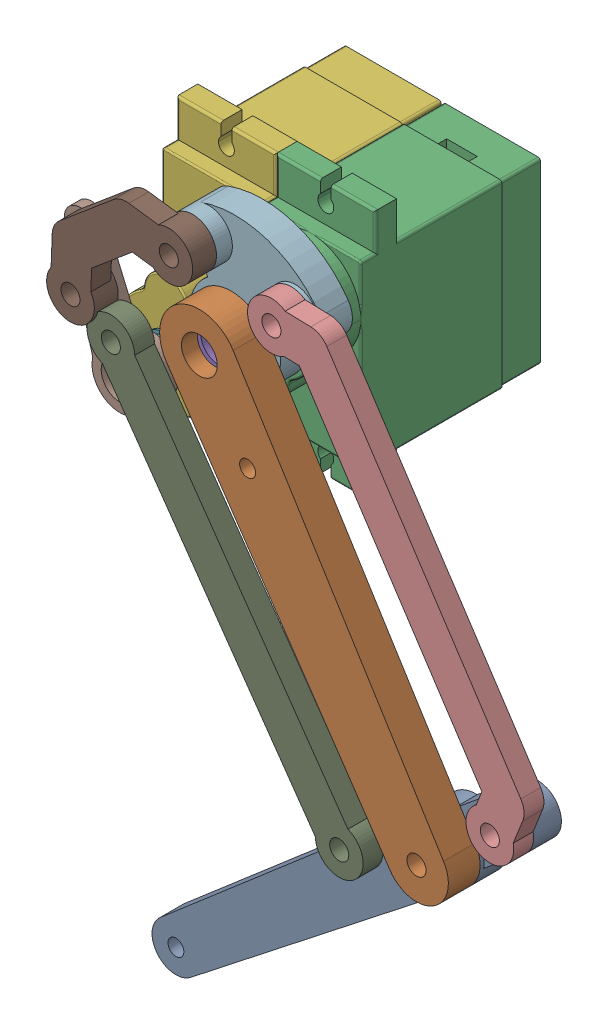
SolidWorks assembly leg_pet bot, configuration Default. Lengths in mm.
Overall size (64.31 93.29 37.3).
16 component instances, 10 part files, 23 mates.
Components (placement in the parent):
- lower_part_leg-1: lower_part_leg [Default] at (33.4104 -25.3824 14.05) x (-0.772475 -0.635046 0) z (0 0 -1) size (61 8 3.5)
- upper_part_leg-1: upper_part_leg [Default] at (6.1 16.5 14.55) x (0.546209 -0.837649 0) z (0 0 1) size (59 10 4)
- MG90servo_assembly(2)^pet bot iteration one-1: MG90servo_assembly(2)^pet bot iteration one [Default] at (12.35 0 -18.25) x (0 1 0) z (1 0 0) size (32.05 32.8 12.51)
  - MG90servo_body(2)^MG90servo_assembly(2)_pet bot iteration one-1: MG90servo_body(2)^MG90servo_assembly(2)_pet bot iteration one [Default] at origin size (32.05 28.5 12.51)
  - MG90servo_shaft(2)^MG90servo_assembly(2)_pet bot iteration one-1: MG90servo_shaft(2)^MG90servo_assembly(2)_pet bot iteration one [Default] at (16.5 28.5 -6.25) x (0.786985 0 0.616972) z (-0.616972 0 0.786985) size (5 4.3 5)
  - MG90servo_gear(2)^MG90servo_assembly(2)_pet bot iteration one-1: MG90servo_gear(2)^MG90servo_assembly(2)_pet bot iteration one [Default] at (16.5 34.45 -6.25) x (0.999514 0 0.031181) z (0.031181 0 -0.999514) (suppressed, hidden)
- microservoArm-1: microservoArm [A3] at (6.1 16.5 16.05) x (0.569885 -0.821724 0) z (0.821724 0.569885 0) size (20.7 3.9 7)
- MG90servo_assembly(2)^pet bot iteration one-2: MG90servo_assembly(2)^pet bot iteration one [Default] at (-12.65 22.75 -18.25) x (0 -1 0) z (-1 0 0) size (32.05 32.8 12.51)
  - MG90servo_body(2)^MG90servo_assembly(2)_pet bot iteration one-1: MG90servo_body(2)^MG90servo_assembly(2)_pet bot iteration one [Default] at origin size (32.05 28.5 12.51)
  - MG90servo_shaft(2)^MG90servo_assembly(2)_pet bot iteration one-1: MG90servo_shaft(2)^MG90servo_assembly(2)_pet bot iteration one [Default] at (16.5 28.5 -6.25) x (0.786985 0 0.616972) z (-0.616972 0 0.786985) size (5 4.3 5)
  - MG90servo_gear(2)^MG90servo_assembly(2)_pet bot iteration one-1: MG90servo_gear(2)^MG90servo_assembly(2)_pet bot iteration one [Default] at (16.5 34.45 -6.25) x (0.999514 0 0.031181) z (0.031181 0 -0.999514) (suppressed, hidden)
- microservoArm-2: microservoArm [A3] at (-6.4 6.25 16.05) x (-0.328049 0.944661 0) z (-0.944661 -0.328049 0) size (20.7 3.9 7)
- connecting_part_leg_2-1: connecting_part_leg_2 [Default] at (-5.0321 12.3438 16.05) x (0.574452 -0.818539 0) z (0 0 1) size (56 6 2.5) (hidden)
- modified connecting rod 3-1: modified connecting rod 3 [Default] at (27.3958 1.8541 15.8) x (0.549575 -0.835444 0) z (0 0 1) size (56 9.5 2.5)
- modified connecting rod-1: modified connecting rod [Default] at (-3.4306 20.7156 17.8) x (-0.764905 -0.644143 0) z (0 0 -1) size (22.17 9.5 3)
- coupler_1-1: coupler_1 [Default] at (6.1 16.5 14.05) x (-0.798551 -0.601927 0) z (0 0 -1) size (18.7 18.24 5.5)
Mates (geometry in assembly coordinates):
- Concentric1: concentric anti-aligned: cylinder of upper_part_leg-1 through (6.1 16.5 8.55) axis (0 0 1) radius 2.25; cylinder of MG90servo_assembly(2)^pet bot iteration one-1/MG90servo_body(2)^MG90servo_assembly(2)_pet bot iteration one-1 through (6.1 16.5 10.25) axis (0 0 -1) radius 6.25
- Coincident3: coincident anti-aligned: plane of upper_part_leg-1 through (6.1 16.5 16.05) normal (0 0 -1); plane of microservoArm-1 through (-2.5623 28.9902 16.05) normal (0 0 1)
- Concentric3: concentric anti-aligned: cylinder of MG90servo_assembly(2)^pet bot iteration one-1/MG90servo_shaft(2)^MG90servo_assembly(2)_pet bot iteration one-1 through (6.1 16.5 11.65) axis (0 0 -1) radius 2.075; cylinder of microservoArm-1 through (6.1 16.5 12.15) axis (0 0 1) radius 2.45
- Coincident4: coincident anti-aligned: plane of MG90servo_assembly(2)^pet bot iteration one-1/MG90servo_shaft(2)^MG90servo_assembly(2)_pet bot iteration one-1 through (6.1 16.5 14.55) normal (0 0 1); plane of microservoArm-1 through (6.1 16.5 14.55) normal (0 0 -1)
- Coincident5: coincident anti-aligned: plane of MG90servo_assembly(2)^pet bot iteration one-1/MG90servo_body(2)^MG90servo_assembly(2)_pet bot iteration one-1 through (-0.15 0 4.5) normal (-1 0 0); plane of MG90servo_assembly(2)^pet bot iteration one-2/MG90servo_body(2)^MG90servo_assembly(2)_pet bot iteration one-1 through (-0.15 22.75 4.5) normal (1 0 0)
- Coincident6: coincident aligned: plane of MG90servo_assembly(2)^pet bot iteration one-1/MG90servo_body(2)^MG90servo_assembly(2)_pet bot iteration one-1 through (12.35 0 4.5) normal (0 0 1); plane of MG90servo_assembly(2)^pet bot iteration one-2/MG90servo_body(2)^MG90servo_assembly(2)_pet bot iteration one-1 through (-12.65 22.75 4.5) normal (0 0 1)
- Concentric4: concentric anti-aligned: cylinder of MG90servo_assembly(2)^pet bot iteration one-2/MG90servo_body(2)^MG90servo_assembly(2)_pet bot iteration one-1 through (-6.4 6.25 10.25) axis (0 0 -1) radius 6.25; cylinder of microservoArm-2 through (-6.4 6.25 12.15) axis (0 0 1) radius 2.45
- Coincident7: coincident anti-aligned: plane of MG90servo_assembly(2)^pet bot iteration one-2/MG90servo_shaft(2)^MG90servo_assembly(2)_pet bot iteration one-1 through (-6.4 6.25 14.55) normal (0 0 1); plane of microservoArm-2 through (-6.4 6.25 14.55) normal (0 0 -1)
- Coincident8: coincident aligned: plane of MG90servo_assembly(2)^pet bot iteration one-1/MG90servo_body(2)^MG90servo_assembly(2)_pet bot iteration one-1 through (12.35 27.4 2.65) normal (0 1 0); plane of MG90servo_assembly(2)^pet bot iteration one-2/MG90servo_body(2)^MG90servo_assembly(2)_pet bot iteration one-1 through (-12.65 27.4 2.65) normal (0 1 0)
- Coincident13: coincident: plane of upper_part_leg-1 through (9.509 18.2893 -8.853) normal (-0.885442 -0.464749 0); line of microservoArm-1 through (16.4057 5.1496 14.65) axis (0 0 1)
- Concentric10: concentric aligned: cylinder of microservoArm-2 through (-9.6149 15.5077 14.65) axis (0 0 1) radius 0.5; cylinder of modified connecting rod-1 through (-9.6149 15.5077 16.55) axis (0 0 1) radius 1.2
- Coincident17: coincident anti-aligned: plane of microservoArm-2 through (-1.4137 -8.1088 16.05) normal (0 0 1); plane of modified connecting rod-1 through (-9.6149 15.5077 16.05) normal (0 0 -1)
- Coincident19: coincident anti-aligned: plane of MG90servo_assembly(2)^pet bot iteration one-1/MG90servo_body(2)^MG90servo_assembly(2)_pet bot iteration one-1 through (0 22.6 -13.25) normal (-1 0 0)
- Coincident20: coincident anti-aligned: plane of MG90servo_assembly(2)^pet bot iteration one-2/MG90servo_body(2)^MG90servo_assembly(2)_pet bot iteration one-1 through (-12.65 22.75 0) normal (0 0 -1)
- Coincident21: coincident anti-aligned: plane of MG90servo_assembly(2)^pet bot iteration one-2/MG90servo_body(2)^MG90servo_assembly(2)_pet bot iteration one-1 through (-12.65 0 4.5) normal (0 -1 0)
- Concentric16: concentric aligned: cylinder of microservoArm-1 through (6.1 16.5 12.15) axis (0 0 1) radius 3.5; cylinder of coupler_1-1 through (6.1 16.5 10.55) axis (0 0 1) radius 3.7
- Coincident22: coincident anti-aligned: plane of modified connecting rod-1 through (2.7536 25.9235 16.05) normal (0 0 -1); plane of coupler_1-1 through (6.1 16.5 16.05) normal (0 0 1)
- Concentric17: concentric anti-aligned: cylinder of modified connecting rod-1 through (2.7536 25.9235 16.55) axis (0 0 1) radius 1.2; cylinder of coupler_1-1 through (2.7536 25.9235 20.55) axis (0 0 -1) radius 1
- Concentric18: concentric aligned: cylinder of modified connecting rod 3-1 through (13.6564 22.7402 17.05) axis (0 0 -1) radius 1.2; cylinder of coupler_1-1 through (13.6564 22.7402 16.55) axis (0 0 -1) radius 1
- Concentric19: concentric anti-aligned: cylinder of lower_part_leg-1 through (33.4104 -25.3824 11.05) axis (0 0 1) radius 1; cylinder of upper_part_leg-1 through (33.4104 -25.3824 18.55) axis (0 0 -1) radius 1.2
- Coincident23: coincident anti-aligned: plane of lower_part_leg-1 through (33.4104 -25.3824 14.55) normal (0 0 1); plane of upper_part_leg-1 through (6.1 16.5 14.55) normal (0 0 -1)
- Concentric20: concentric anti-aligned: cylinder of lower_part_leg-1 through (41.1352 -19.032 11.05) axis (0 0 1) radius 1; cylinder of modified connecting rod 3-1 through (41.1352 -19.032 17.05) axis (0 0 -1) radius 1.2
- Coincident24: coincident anti-aligned: plane of lower_part_leg-1 through (41.1352 -19.032 14.55) normal (0 0 1); plane of modified connecting rod 3-1 through (27.3958 1.8541 14.55) normal (0 0 -1)
